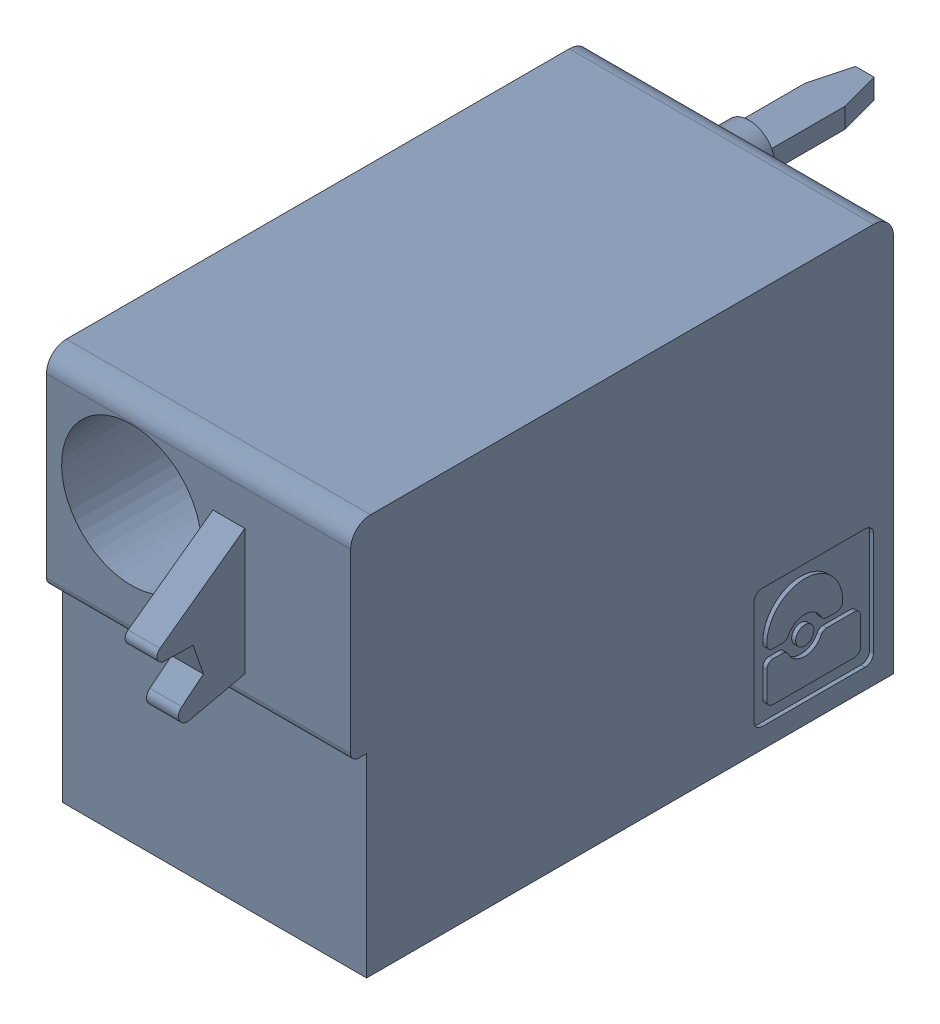
SolidWorks assembly J80, configuration Default. Lengths in mm.
Overall size (7.62 10 19.2).
2 component instances, 1 part files, 0 mates.
Components (placement in the parent):
- 1790487-1: 1790487 [Default] at (221.385 -5.67 -10.6) x (0 1 0) z (1 0 0) size (10 19.2 7.62)
  - ffkdsa1-v2-7.62-1: ffkdsa1-v2-7.62 [Default] at (-15.6914 -27.508 9.12) x (0 -1 0) z (0 0 1) size (19.2 10 7.62)
